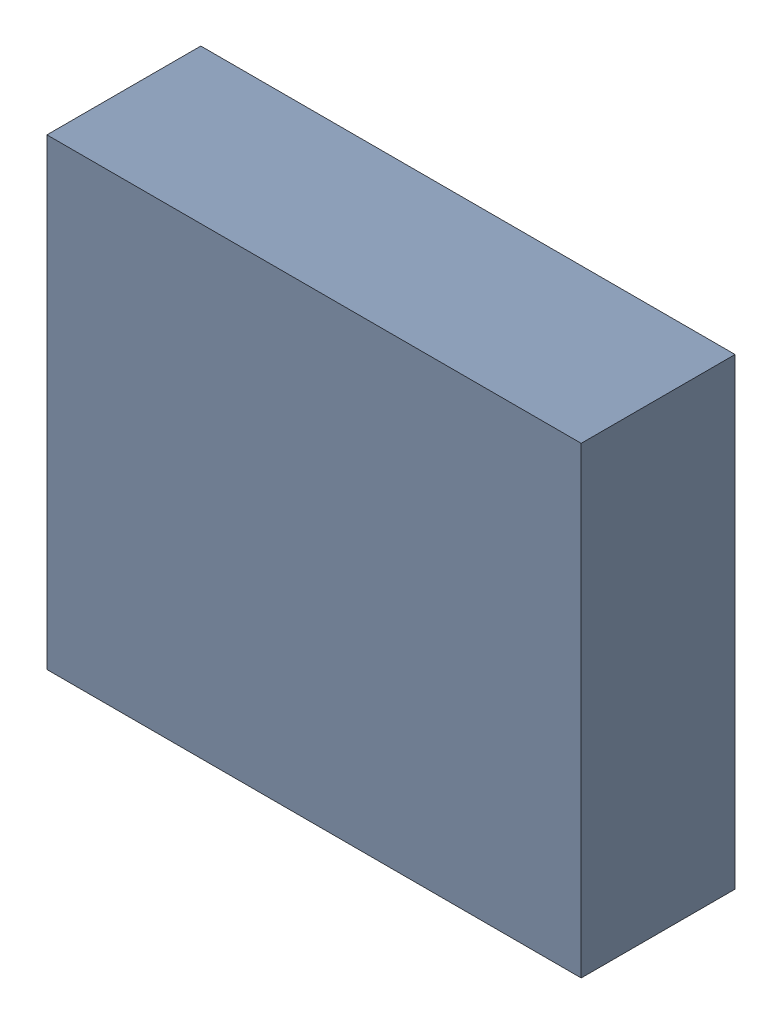
SolidWorks assembly SUDZOR1Kanaloa_v2.0.0_Power, configuration Default. Lengths in mm.
Overall size (7.5 6.5 2.16).
2 component instances, 1 part files, 0 mates.
Components (placement in the parent):
- 425993600-1: 425993600 [Default] at (134.875 37.65 -3.3124) size (7.5 6.5 2.16)
  - Extruded_7-1: Extruded_7 [Default] at origin size (7.5 6.5 2.16)
